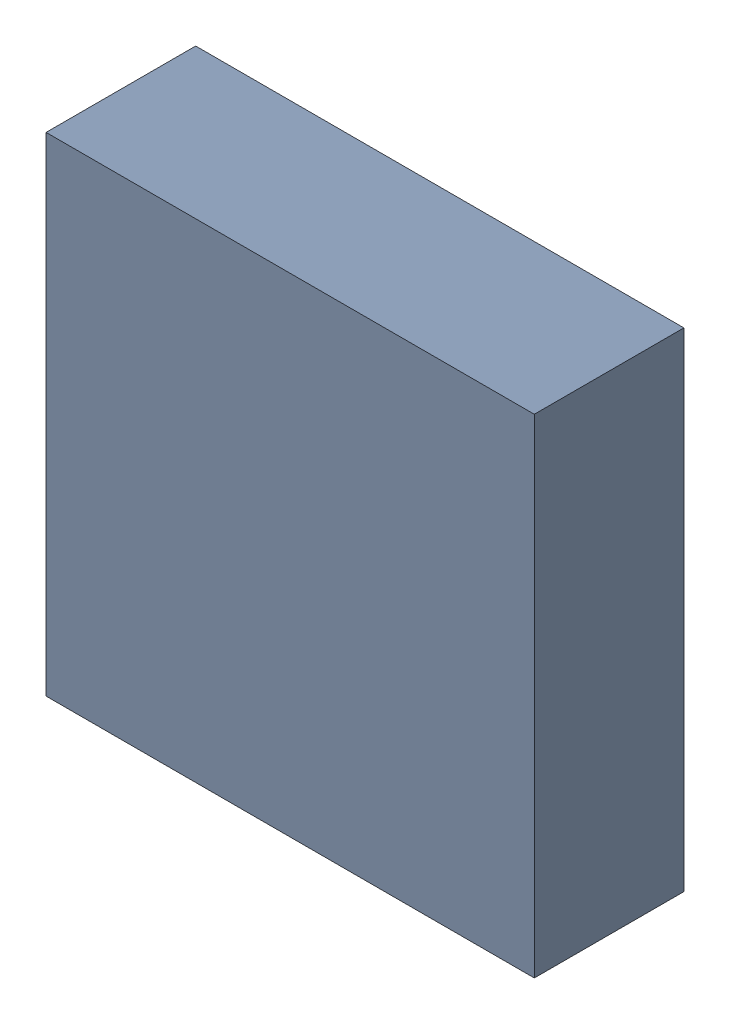
SolidWorks assembly U5, configuration Default. Lengths in mm.
Overall size (3.1 3.1 0.95).
2 component instances, 1 part files, 0 mates.
Components (placement in the parent):
- 870940320-1: 870940320 [Default] at (30.2506 29.8936 0.05) size (3.1 3.1 0.95)
  - Extruded_18-1: Extruded_18 [Default] at origin size (3.1 3.1 0.95)
